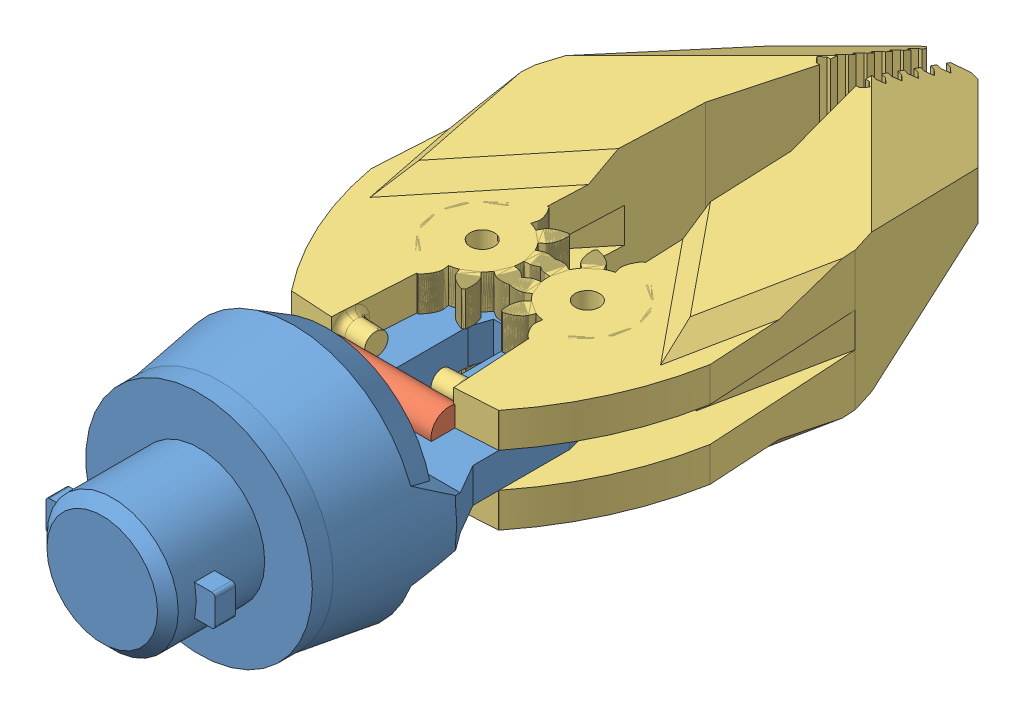
SolidWorks assembly Grasper Assembly, configuration Default. Lengths in mm.
Overall size (51.49 36 114.44).
4 component instances, 3 part files, 9 mates.
Components (placement in the parent):
- Grasper Body-1: Grasper Body [Default] at (0 0 18.5286) size (37.45 36 58.53)
- Spring-1: Spring [Default] at (0 2.9735 -8.6) x (1 0 0) z (0 -0.96148 0.274876) size (18 5.2 5.2)
- Grasper-8: Grasper [Domyślna] at (7.6 0 -30) x (0.060502 0 0.998168) z (0 1 0) size (80.6 25.49 20)
- Grasper-9: Grasper [Domyślna] at (-7.6 0 -30) x (-0.060502 0 0.998168) z (0 -1 0) size (80.6 25.49 20)
Mates (geometry in assembly coordinates):
- Wspólnie1: coincident aligned: plane of Grasper Body-1 through (0 0 18.5286) normal (1 0 0); plane of assembly through (0 0 0) normal (1 0 0)
- Wspólnie2: coincident: line of Grasper Body-1 through (0 0 31.0286) axis (0 0 -1); plane of assembly
- Wspólnie3: coincident aligned: plane of Grasper Body-1 through (0 0 18.5286) normal (1 0 0); plane of assembly through (0 0 0) normal (1 0 0)
- Wspólnie4: coincident anti-aligned: plane of Grasper Body-1 through (18.7246 0 0) normal (0 0 -1); plane of assembly through (0 0 0) normal (0 0 1)
- Odległość3: distance = 6 mm anti-aligned: cylinder of Spring-1 through (9 2.9735 -8.6) axis (-1 0 0) radius 2.6; plane of Grasper Body-1 through (18.7246 0 0) normal (0 0 -1)
- Wspólnie5: coincident aligned: plane of Spring-1; plane of assembly through (0 0 0) normal (1 0 0)
- Stycznie1: tangent aligned: plane of ? through (-7.6 10 -30) normal (0 1 0); cylinder of Spring-1 through (9 7.4 -8.6) axis (-1 0 0) radius 2.6
- Koncentryczne1: concentric anti-aligned: cylinder of Grasper Body-1 through (7.6 -7.5 -30) axis (0 1 0) radius 1.5; cylinder of Grasper-8 through (7.6 8.3674 -30) axis (0 -1 0) radius 1.75
- Wspólnie6: coincident aligned: plane of Grasper-8 through (7.6 0 -30) normal (0 1 0); plane of assembly through (0 0 0) normal (0 1 0)
